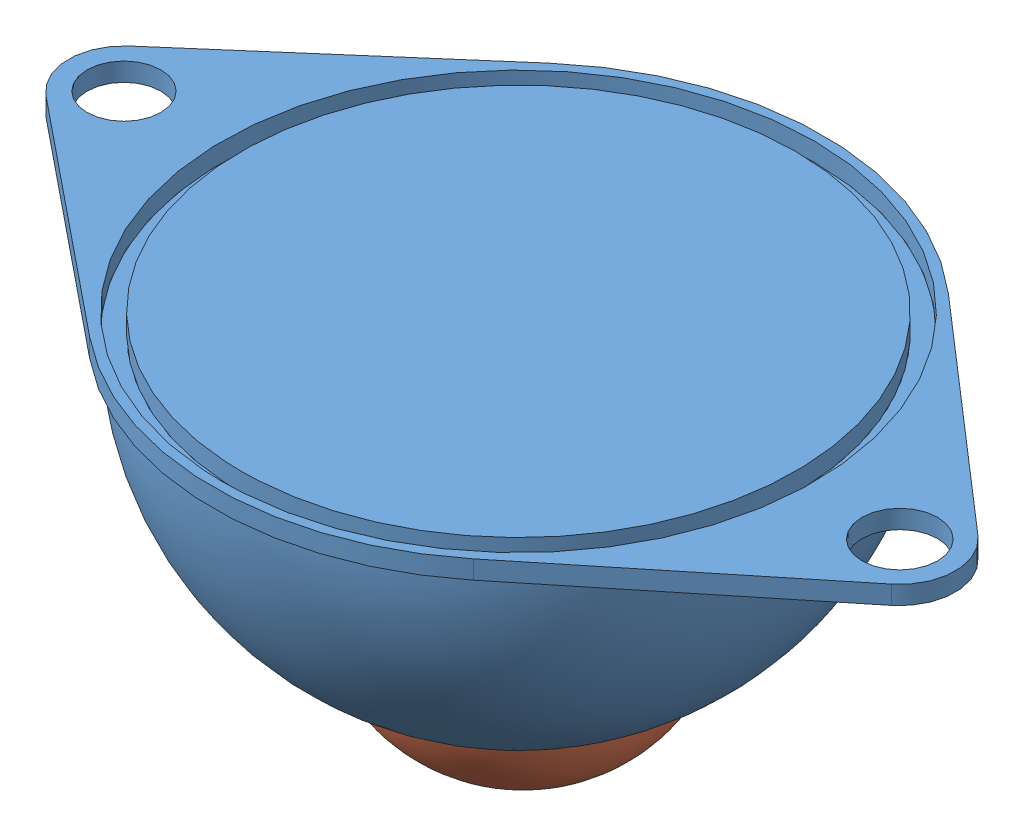
SolidWorks assembly free caster wheel (1), configuration Default. Lengths in mm.
Overall size (24 10.17 16.5).
2 component instances, 2 part files, 0 mates.
Components (placement in the parent):
- Part7-1: Part7 [Default] at (19.6841 32.5402 35.2847) size (24 7.57 16.5)
- Part8-2: Part8 [Default] at (19.903 25.9461 35.3791) size (8 8 8)
